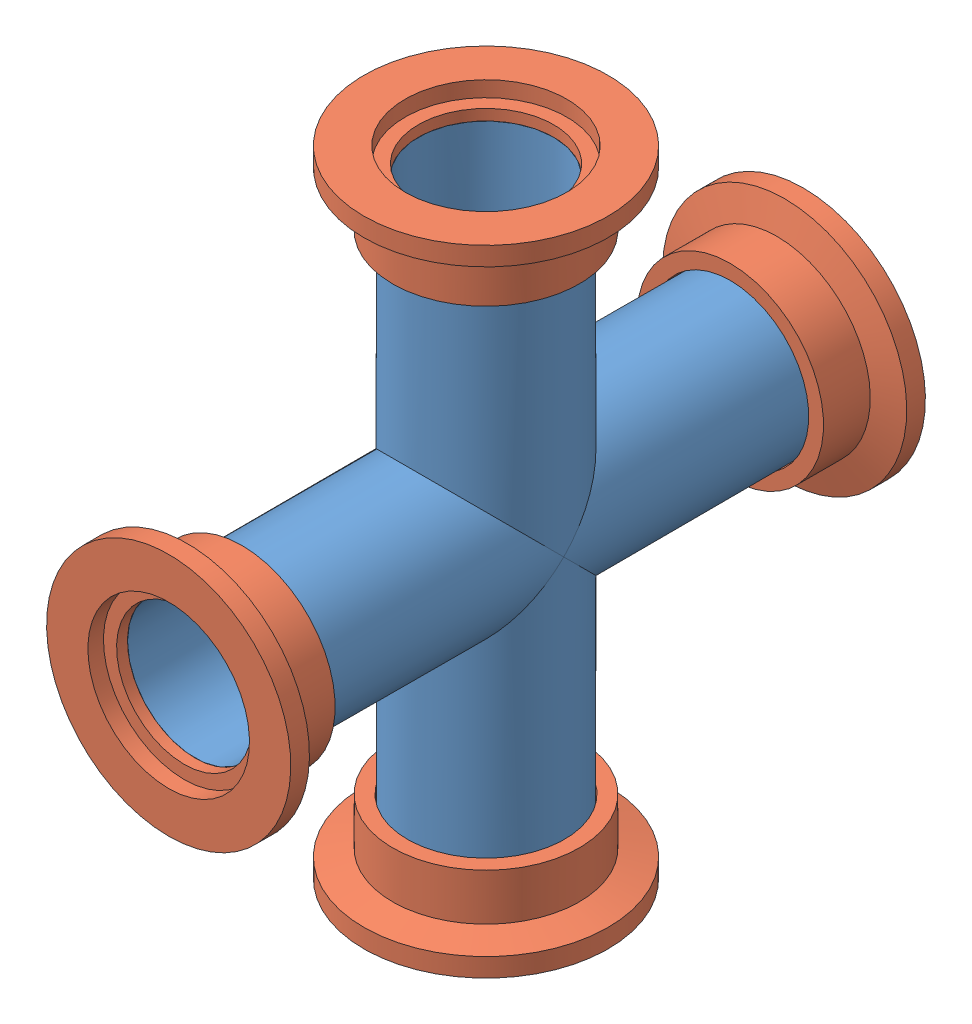
SolidWorks assembly 725001, configuration Default. Lengths in mm.
Overall size (55.2 103.63 103.63).
5 component instances, 2 part files, 8 mates.
Components (placement in the parent):
- 405501-1: 405501 [Default] at (40.0046 52.8286 68.3081) size (25.4 95 95)
- 713002-1: 713002 [Default] at (40.0046 104.6446 68.3081) size (39.88 11.94 39.88)
- 713002-2: 713002 [Default] at (40.0046 52.8286 120.1241) x (1 0 0) z (0 -1 0) size (39.88 11.94 39.88)
- 713002-3: 713002 [Default] at (40.0046 52.8286 16.4921) x (1 0 0) z (0 1 0) size (39.88 11.94 39.88)
- 713002-5: 713002 [Default] at (40.0046 1.0126 68.3081) x (-0.837169 0 -0.546944) z (-0.546944 0 0.837169) size (39.88 11.94 39.88)
Mates (geometry in assembly coordinates):
- Coincident3: coincident: plane of 405501-1 through (40.0046 100.3266 68.3081) normal (0 1 0); plane of 713002-1 through (52.8316 100.3266 68.3081) normal (0 -1 0)
- Concentric3: concentric anti-aligned: cylinder of 405501-1 through (40.0046 100.3266 68.3081) axis (0 -1 0) radius 12.7; cylinder of 713002-1 through (40.0046 104.6446 68.3081) axis (0 1 0) radius 15.24
- Coincident4: coincident: plane of 405501-1 through (40.0046 52.8286 115.8061) normal (0 0 1); plane of 713002-2 through (52.8316 52.8286 115.8061) normal (0 0 -1)
- Concentric4: concentric anti-aligned: cylinder of 405501-1 through (40.0046 52.8286 115.8061) axis (0 0 -1) radius 12.7; cylinder of 713002-2 through (40.0046 52.8286 120.1241) axis (0 0 1) radius 15.24
- Coincident5: coincident: plane of 405501-1 through (40.0046 5.3306 68.3081) normal (0 -1 0); plane of 713002-5 through (29.2662 5.3306 61.2924) normal (0 1 0)
- Concentric5: concentric aligned: cylinder of 405501-1 through (40.0046 100.3266 68.3081) axis (0 -1 0) radius 12.7; cylinder of 713002-5 through (40.0046 1.0126 68.3081) axis (0 -1 0) radius 12.827
- Coincident6: coincident: plane of 405501-1 through (40.0046 52.8286 20.8101) normal (0 0 -1); plane of 713002-3 through (52.8316 52.8286 20.8101) normal (0 0 1)
- Concentric6: concentric aligned: cylinder of 405501-1 through (40.0046 52.8286 115.8061) axis (0 0 -1) radius 12.7; cylinder of 713002-3 through (40.0046 52.8286 16.4921) axis (0 0 -1) radius 15.24
